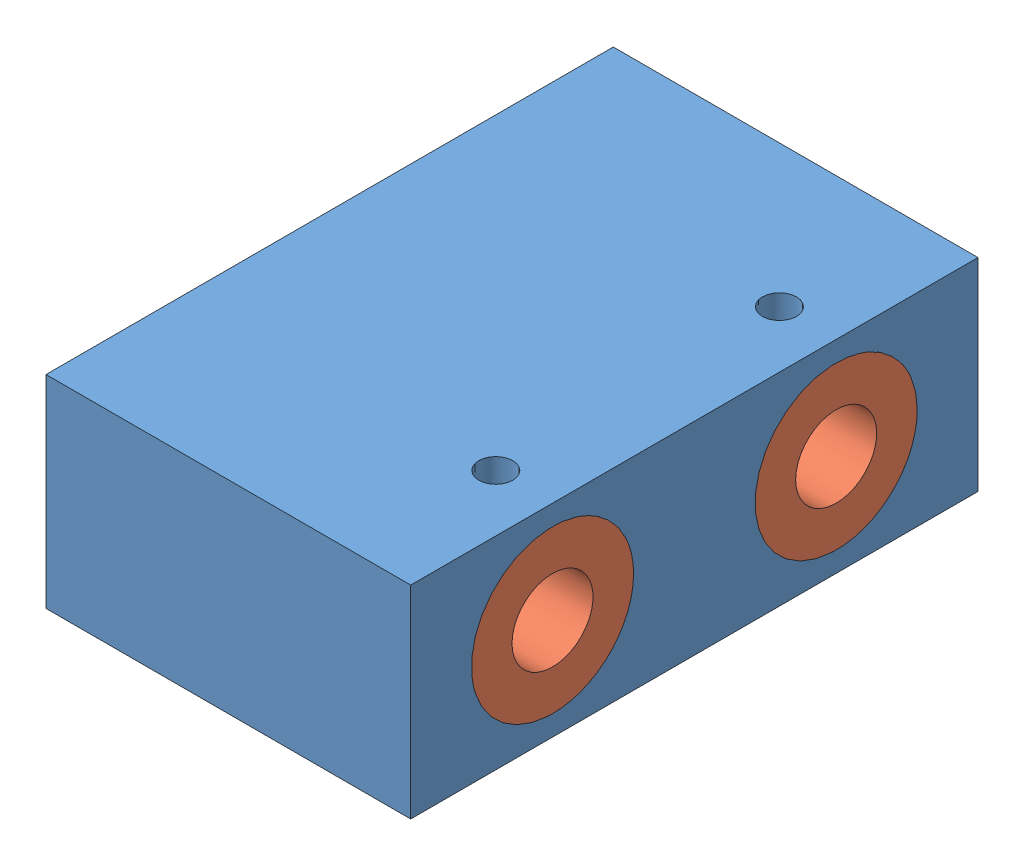
SolidWorks assembly con_truot_s4_as, configuration Default. Lengths in mm.
Overall size (45 28.02 70).
5 component instances, 2 part files, 8 mates.
Components (placement in the parent):
- con_truot_s4-1: con_truot_s4 [Default] at (24.0458 23.4144 55.2485) size (45 25 70)
- bat_lot-1: bat_lot [Default] at (46.5458 35.9144 72.7485) x (0 0.967524 -0.252781) z (0 0.252781 0.967524) size (20 10 20)
- bat_lot-2: bat_lot [Default] at (46.5458 35.9144 37.7485) x (0 0.967524 -0.252781) z (0 0.252781 0.967524) size (20 10 20)
- bat_lot-3: bat_lot [Default] at (1.5458 35.9144 72.7485) x (0 0.603074 -0.797685) z (0 -0.797685 -0.603074) size (20 10 20)
- bat_lot-4: bat_lot [Default] at (1.5458 35.9144 37.7485) x (0 0.603074 -0.797685) z (0 -0.797685 -0.603074) size (20 10 20)
Mates (geometry in assembly coordinates):
- Concentric1: concentric anti-aligned: cylinder of con_truot_s4-1 through (75.5458 35.9144 72.7485) axis (-1 0 0) radius 6; cylinder of bat_lot-1 through (36.5458 35.9144 72.7485) axis (1 0 0) radius 5
- Coincident1: coincident aligned: plane of con_truot_s4-1 through (46.5458 48.4144 106.2485) normal (1 0 0); plane of bat_lot-1 through (46.5458 35.9144 72.7485) normal (1 0 0)
- Coincident2: coincident anti-aligned: circle of con_truot_s4-1; cylinder of bat_lot-2 through (36.5458 35.9144 37.7485) axis (1 0 0) radius 6
- Coincident3: coincident aligned: plane of con_truot_s4-1 through (46.5458 48.4144 106.2485) normal (1 0 0); plane of bat_lot-2 through (46.5458 35.9144 37.7485) normal (1 0 0)
- Concentric2: concentric aligned: cylinder of con_truot_s4-1 through (75.5458 35.9144 72.7485) axis (-1 0 0) radius 6; cylinder of bat_lot-3 through (11.5458 35.9144 72.7485) axis (-1 0 0) radius 6
- Coincident4: coincident aligned: plane of con_truot_s4-1 through (1.5458 48.4144 106.2485) normal (-1 0 0); plane of bat_lot-3 through (1.5458 35.9144 72.7485) normal (-1 0 0)
- Concentric3: concentric aligned: cylinder of con_truot_s4-1 through (75.5458 35.9144 37.7485) axis (-1 0 0) radius 6; cylinder of bat_lot-4 through (11.5458 35.9144 37.7485) axis (-1 0 0) radius 5
- Coincident5: coincident aligned: plane of con_truot_s4-1 through (1.5458 48.4144 106.2485) normal (-1 0 0); plane of bat_lot-4 through (1.5458 35.9144 37.7485) normal (-1 0 0)
